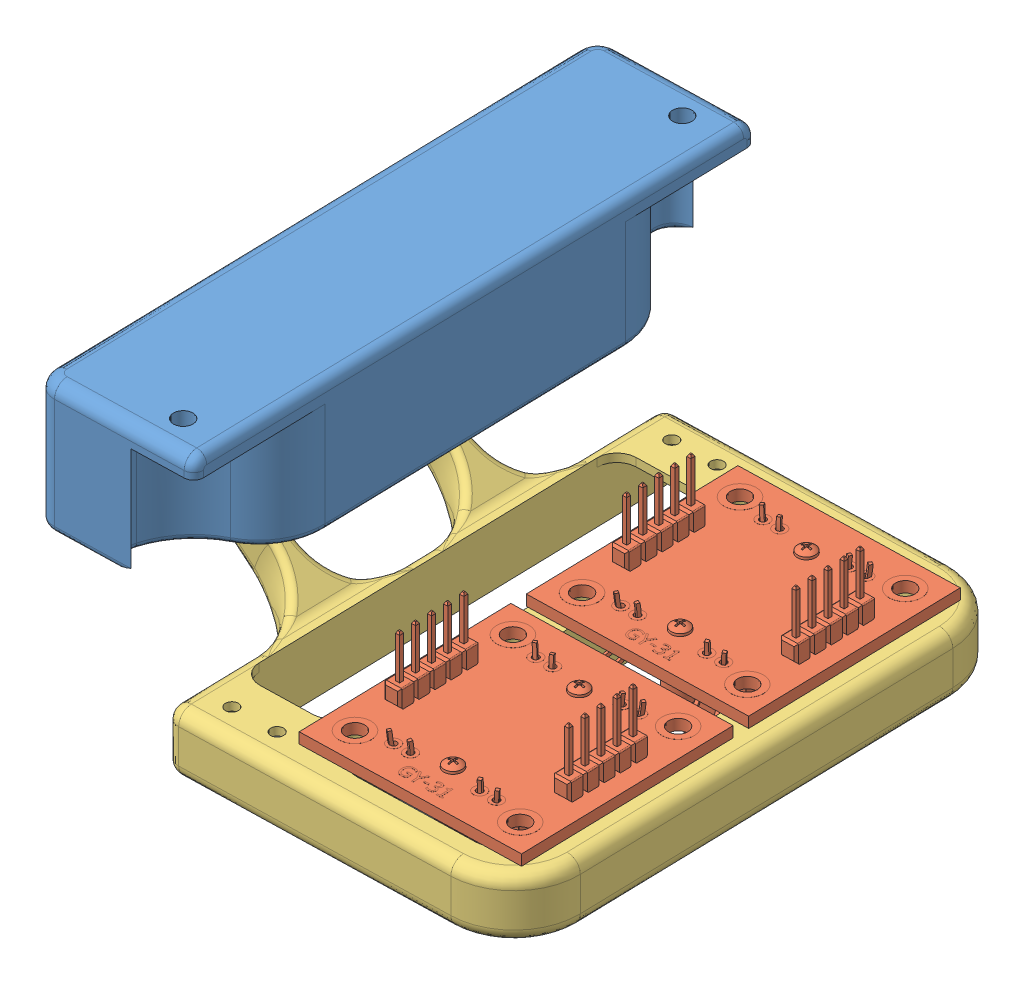
SolidWorks assembly Montagem-Suporte-Sensor, configuration Valor predeterminado. Lengths in mm.
Overall size (80.06 54.08 89.82).
4 component instances, 3 part files, 7 mates.
Components (placement in the parent):
- Suporte-Trava-Array-1: Suporte-Trava-Array [Valor predeterminado] at (8.0725 57.4547 60.6544) x (0.000123 -1 -0.000003) z (-0.024762 0 -0.999693) size (30 34.04 89)
- Color_sensor-1: Color_sensor [Valor predeterminado] at (35.7272 20.9236 62.0431) x (0.999693 0 -0.024762) z (-0.024762 0 -0.999693) size (33.5 25.76 33.5)
- Suporte-Array-Movel (1)-2: Suporte-Array-Movel (1) [Valor predeterminado] at (-20.1111 34.8821 57.633) x (0.999693 0 -0.024762) z (0.024762 0 0.999693) size (77 25.86 78.95)
- Color_sensor-2: Color_sensor [Valor predeterminado] at (34.837 20.9236 26.1041) x (0.999693 0 -0.024762) z (-0.024762 0 -0.999693) size (33.5 25.76 33.5)
Mates (geometry in assembly coordinates):
- Coincidente9: coincident anti-aligned: plane of Color_sensor-1 through (15.3123 20.9891 79.3039) normal (0 -1 0); plane of Suporte-Array-Movel (1)-2 through (-0.3179 20.9891 84.326) normal (0 1 0)
- Concêntrico9: concentric aligned: circle of Color_sensor-1; circle of Suporte-Array-Movel (1)-2
- Concêntrico10: concentric aligned: circle of Suporte-Array-Movel (1)-2; circle of Color_sensor-2
- Coincidente13: coincident anti-aligned: plane of Suporte-Array-Movel (1)-2 through (-0.3179 20.9891 84.326) normal (0 1 0); plane of Color_sensor-2 through (14.4221 20.9891 43.3649) normal (0 -1 0)
- Concêntrico11: concentric aligned: circle of Suporte-Array-Movel (1)-2; circle of Color_sensor-2
- Concêntrico12: concentric: circle of Suporte-Trava-Array-1; circle of Suporte-Array-Movel (1)-2
- Distância2: distance = 0.5 mm anti-aligned: plane of Suporte-Array-Movel (1)-2 through (-20.7941 34.8821 30.0614) normal (-0.024762 0 -0.999693); plane of Suporte-Trava-Array-1 through (-24.682 57.4507 29.6576) normal (0.024762 0 0.999693)
